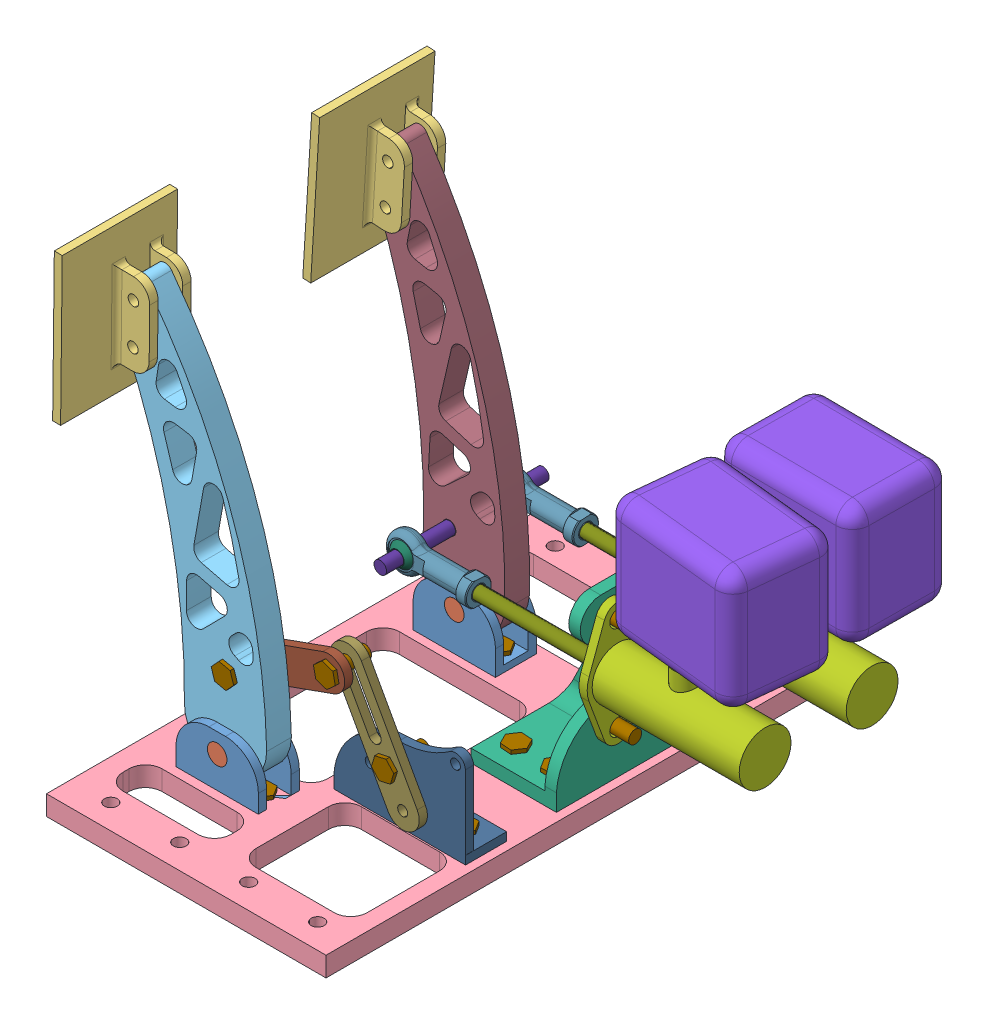
SolidWorks assembly Final Assembly, configuration Default. Lengths in mm.
Overall size (296.55 297.46 300.01).
42 component instances, 17 part files, 74 mates.
Components (placement in the parent):
- braket1-4: braket1 [Default] at (-141.1694 -572.6456 150.5631) size (50.04 35.05 24.89)
- screw-4: screw [Default] at (-131.3986 -621.8907 144.9751) size (24.68 21.38 30.48)
- throttle pedal-2: throttle pedal [Default] at (-246.1503 -359.0147 167.9481) x (0 0 -1) z (0.998164 -0.060575 0) size (70.1 89.92 24.82)
- pedal box base-2: pedal box base [Default] at (-213.3196 -624.1778 279.5672) x (-0.00023 0 1) z (0 1 0) size (299.97 169.93 11.99)
- braket1-5: braket1 [Default] at (-141.1997 -576.7096 294.5962) x (1 0 0.00023) z (-0.00023 0 1) size (50.04 35.05 24.89)
- throttle bar-3: throttle bar [Default] at (-198.6716 -410.0837 299.536) x (0.999937 -0.011241 0.00023) z (-0.00023 0 1) size (88.75 235.49 14.99)
- throttle pedal-3: throttle pedal [Default] at (-257.4721 -366.0384 311.9545) x (0.00023 0 -1) z (0.999937 -0.011241 0.00023) size (70.1 89.92 24.82)
- screw-5: screw [Default] at (-131.4275 -625.9547 289.0104) x (1 0 0.00023) z (-0.00023 0 1) size (24.68 21.38 30.48)
- brake holder 2-2: brake holder 2 [Default] at (-77.2892 -529.542 159.1215) x (-0.00023 0 1) z (-1 0 -0.00023) size (129.92 100.94 51.96)
- master cylinder-1: master cylinder [Default] at (-72.3192 -552.372 195.428) x (-0.00023 0 1) z (-1 0 -0.00023) size (37.59 74.93 94.34)
- master cylinder-2: master cylinder [Default] at (-72.3042 -552.372 130.404) x (-0.00023 0 1) z (-1 0 -0.00023) size (37.59 74.93 94.34)
- reservoir-1: reservoir [Default] at (-28.0647 -433.5 171.0985) x (-0.00841 0 0.999965) z (0 -1 0) size (59.69 84.07 93.98)
- reservoir-2: reservoir [Default] at (-31.9608 -433.5 236.2853) x (-0.103359 0 0.994644) z (0 -1 0) size (59.69 84.07 93.98)
- screw2-2: screw2 [Default] at (-195.652 -605.839 156.9169) x (1 0 0) z (0 -1 0) size (13.97 12.36 24.64)
- screw2-3: screw2 [Default] at (-165.68 -605.839 156.9169) x (1 0 0) z (0 -1 0) size (13.97 12.36 24.64)
- screw2-4: screw2 [Default] at (-195.6851 -609.903 300.9349) x (1 0 0) z (0 -1 0) size (13.97 12.36 24.64)
- screw2-5: screw2 [Default] at (-165.7131 -609.903 300.9418) x (1 0 0) z (0 -1 0) size (13.97 12.36 24.64)
- screw2-6: screw2 [Default] at (-86.566 -529.8891 119.0806) x (0.00023 0 -1) z (1 0 0.00023) size (13.97 12.36 24.64)
- screw2-7: screw2 [Default] at (-86.581 -517.7001 184.1072) x (0.000127 0.834841 -0.550491) z (1 0 0.00023) size (13.97 12.36 24.64)
- screw2-8: screw2 [Default] at (-86.5831 -568.29 193.1755) x (-0.000072 0.949913 0.312516) z (1 0 0.00023) size (13.97 12.36 24.64)
- screw2-9: screw2 [Default] at (-86.5715 -584.4532 142.7686) x (-0.000165 -0.696104 0.717941) z (1 0 0.00023) size (13.97 12.36 24.64)
- throttle link holder-1: throttle link holder [Default] at (-136.2849 -547.7292 283.2435) x (-1 0 -0.00023) z (0.00023 0 -1) size (80.01 56.04 24.97)
- screw2-10: screw2 [Default] at (-80.8684 -604.823 263.1153) x (1 0 0) z (0 -1 0) size (13.97 12.36 24.64)
- screw2-11: screw2 [Default] at (-105.7245 -602.029 106.8996) x (1 0 0) z (0 -1 0) size (13.97 12.36 24.64)
- screw2-12: screw2 [Default] at (-80.8325 -602.029 106.9053) x (1 0 0) z (0 -1 0) size (13.97 12.36 24.64)
- screw2-13: screw2 [Default] at (-139.2903 -604.823 256.6805) x (0.662504 0 -0.749058) z (0 -1 0) size (13.97 12.36 24.64)
- screw2-14: screw2 [Default] at (-80.8555 -602.029 206.8573) x (1 0 0) z (0 -1 0) size (13.97 12.36 24.64)
- screw2-15: screw2 [Default] at (-127.2522 -602.029 205.0994) x (-0.408462 0 -0.912775) z (0 -1 0) size (13.97 12.36 24.64)
- link2-1: link2 [Default] at (-162.0656 -546.6237 294.566) x (0.941416 0.337249 0.000216) z (-0.00023 0 1) size (70.1 20.07 4.98)
- link1-1: link1 [Default] at (-128.4449 -575.7285 283.2453) x (0.483636 -0.875269 0.000111) z (-0.00023 0 1) size (90.26 20.15 4.98)
- screw2-17: screw2 [Default] at (-203.9237 -556.3573 316.8068) x (-0.968749 0.248043 -0.000223) z (0.00023 0 -1) size (13.97 12.36 24.64)
- screw2-18: screw2 [Default] at (-118.1953 -592.8933 290.5121) x (-0.335719 -0.941962 -0.000077) z (0.00023 0 -1) size (13.97 12.36 24.64)
- screw2-21: screw2 [Default] at (-131.6018 -534.6293 301.8374) x (0.937139 -0.348957 0.000215) z (0.00023 0 -1) size (13.97 12.36 24.64)
- brake pedal bar2-1: brake pedal bar2 [Default] at (-189.598 -405.9081 155.5161) x (0.998164 -0.060575 0) z (0 0 1) size (88.75 235.49 14.99)
- rotula-1: rotula [Default] at (-199.8553 -552.0509 124.3889) x (-0.000012 0.998565 0.053558) z (-0.00023 -0.053558 0.998565) size (22.31 54.17 16)
- rotula2-1: rotula2 [Default] at (-199.8567 -552.3723 138.3813) x (-0.466077 0.884744 0) z (-0.884744 -0.466077 0) size (16 13.43 16)
- master cy plunge-4: master cy plunge [Default] at (-38.7407 -560.307 138.1282) x (0.000067 -0.956892 -0.290446) z (-1 0 -0.00023) size (25.4 25.4 118.11)
- master cy plunge-5: master cy plunge [Default] at (-38.7514 -550.0649 184.7345) x (0.000067 0.956892 -0.290446) z (-1 0 -0.00023) size (25.4 25.4 118.11)
- rotula-3: rotula [Default] at (-199.873 -552.0509 201.5085) x (-0.000012 -0.998565 0.053558) z (0.00023 -0.053558 -0.998565) size (22.31 54.17 16)
- rotula2-3: rotula2 [Default] at (-199.868 -552.3723 187.5161) x (-0.466077 0.884744 -0.000214) z (0.884744 0.466077 0.000407) size (16 13.43 16)
- rod-1: rod [Default] at (-188.1558 -556.2726 113.6061) size (7.62 7.62 41.91)
- rod-2: rod [Default] at (-188.1558 -556.2726 170.5021) size (7.62 7.62 41.91)
Mates (geometry in assembly coordinates):
- Concentric27: concentric anti-aligned: circle of braket1-4; circle of screw-4
- Coincident27: coincident aligned: circle of braket1-4; circle of screw-4
- Coincident28: coincident aligned: circle of braket1-4; circle of pedal box base-2
- Coincident29: coincident aligned: circle of braket1-4; circle of pedal box base-2
- Concentric29: concentric aligned: circle of pedal box base-2; circle of braket1-5
- Coincident32: coincident aligned: circle of pedal box base-2; circle of braket1-5
- Coincident33: coincident aligned: circle of pedal box base-2; circle of braket1-5
- Coincident35: coincident aligned: circle of braket1-5; circle of throttle bar-3
- Concentric30: concentric anti-aligned: circle of braket1-5; circle of throttle bar-3
- Concentric31: concentric anti-aligned: circle of throttle bar-3; circle of throttle pedal-3
- Concentric32: concentric anti-aligned: circle of throttle bar-3; circle of throttle pedal-3
- Coincident36: coincident anti-aligned: plane of throttle bar-3 through (-198.6716 -410.0837 299.536) normal (0.00023 0 -1); plane of throttle pedal-3 through (-232.6646 -367.1725 299.5282) normal (-0.00023 0 1)
- Concentric33: concentric anti-aligned: circle of braket1-5; circle of screw-5
- Coincident37: coincident aligned: circle of braket1-5; circle of screw-5
- Concentric40: concentric aligned: circle of pedal box base-2; circle of brake holder 2-2
- Concentric41: concentric aligned: circle of pedal box base-2; circle of brake holder 2-2
- Coincident48: coincident anti-aligned: plane of pedal box base-2 through (-213.3196 -612.189 279.5672) normal (0 1 0); plane of brake holder 2-2 through (-84.2752 -612.189 97.8892) normal (0 -1 0)
- Concentric49: concentric aligned: circle of brake holder 2-2; circle of master cylinder-2
- Concentric50: concentric aligned: circle of brake holder 2-2; circle of master cylinder-2
- Coincident52: coincident aligned: circle of brake holder 2-2; circle of master cylinder-2
- Concentric51: concentric aligned: circle of brake holder 2-2; circle of master cylinder-1
- Concentric52: concentric aligned: circle of brake holder 2-2; circle of master cylinder-1
- Coincident53: coincident aligned: circle of brake holder 2-2; circle of master cylinder-1
- Coincident55: coincident anti-aligned: circle of master cylinder-2; circle of reservoir-1
- Coincident56: coincident anti-aligned: circle of master cylinder-1; circle of reservoir-2
- Coincident59: coincident anti-aligned: circle of braket1-4; circle of screw2-2
- Coincident60: coincident anti-aligned: circle of braket1-4; circle of screw2-3
- Coincident61: coincident anti-aligned: circle of braket1-5; circle of screw2-4
- Coincident62: coincident anti-aligned: circle of pedal box base-2; circle of screw2-5
- Concentric62: concentric anti-aligned: circle of brake holder 2-2; circle of screw2-6
- Coincident64: coincident anti-aligned: plane of brake holder 2-2 through (-84.2892 -529.542 159.1199) normal (-1 0 -0.00023); circle of screw2-6
- Concentric63: concentric anti-aligned: circle of brake holder 2-2; circle of screw2-9
- Coincident65: coincident anti-aligned: plane of brake holder 2-2 through (-84.2892 -529.542 159.1199) normal (-1 0 -0.00023); circle of screw2-9
- Concentric64: concentric anti-aligned: circle of brake holder 2-2; circle of screw2-7
- Coincident66: coincident anti-aligned: plane of brake holder 2-2 through (-84.2892 -529.542 159.1199) normal (-1 0 -0.00023); circle of screw2-7
- Concentric65: concentric anti-aligned: circle of brake holder 2-2; circle of screw2-8
- Coincident67: coincident anti-aligned: plane of brake holder 2-2 through (-84.2892 -529.542 159.1199) normal (-1 0 -0.00023); circle of screw2-8
- Coincident68: coincident aligned: circle of pedal box base-2; circle of throttle link holder-1
- Concentric69: concentric anti-aligned: circle of pedal box base-2; circle of throttle link holder-1
- Concentric71: concentric anti-aligned: circle of brake holder 2-2; circle of screw2-12
- Coincident70: coincident anti-aligned: circle of brake holder 2-2; circle of screw2-12
- Concentric72: concentric anti-aligned: circle of brake holder 2-2; circle of screw2-11
- Coincident71: coincident anti-aligned: circle of brake holder 2-2; circle of screw2-11
- Concentric73: concentric anti-aligned: circle of brake holder 2-2; circle of screw2-15
- Coincident72: coincident anti-aligned: circle of brake holder 2-2; circle of screw2-15
- Concentric74: concentric anti-aligned: circle of brake holder 2-2; circle of screw2-14
- Coincident73: coincident anti-aligned: circle of brake holder 2-2; circle of screw2-14
- Concentric76: concentric aligned: circle of throttle link holder-1; circle of screw2-13
- Coincident75: coincident aligned: circle of throttle link holder-1; circle of screw2-13
- Concentric77: concentric anti-aligned: circle of throttle link holder-1; circle of screw2-10
- Coincident76: coincident anti-aligned: circle of throttle link holder-1; circle of screw2-10
- Concentric78: concentric aligned: cylinder of throttle bar-3 through (-191.4391 -553.2635 285.8216) axis (-0.00023 0 1) radius 3.937; circle of link2-1
- Coincident79: coincident anti-aligned: circle of throttle link holder-1; circle of link1-1
- Concentric80: concentric anti-aligned: cylinder of link2-1 through (-191.4411 -553.2635 294.5592) axis (-0.00023 0 1) radius 3.937; circle of screw2-17
- Coincident80: coincident anti-aligned: plane of throttle bar-3 through (-198.675 -410.0837 314.522) normal (-0.00023 0 1); circle of screw2-17
- Concentric82: concentric anti-aligned: circle of link1-1; circle of screw2-18
- Coincident82: coincident anti-aligned: plane of link1-1 through (-144.3331 -536.3882 288.2201) normal (-0.00023 0 1); circle of screw2-18
- Concentric98: concentric anti-aligned: circle of link2-1; circle of screw2-21
- Coincident96: coincident anti-aligned: plane of link2-1 through (-191.4422 -553.2635 299.5376) normal (-0.00023 0 1); circle of screw2-21
- Concentric99: concentric anti-aligned: circle of link1-1; circle of screw2-21
- Concentric100: concentric aligned: cylinder of screw-4 through (-191.8591 -589.075 175.4551) axis (0 0 -1) radius 5.969; cylinder of brake pedal bar2-1 through (-191.8591 -589.075 170.5021) axis (0 0 -1) radius 5.969
- Coincident97: coincident anti-aligned: plane of braket1-4 through (-216.8781 -664.4229 155.5161) normal (0 0 1); plane of brake pedal bar2-1 through (-189.598 -405.9081 155.5161) normal (0 0 -1)
- Concentric101: concentric anti-aligned: cylinder of throttle pedal-2 through (-232.0813 -373.3215 204.4619) axis (0 0 -1) radius 3.1963; cylinder of brake pedal bar2-1 through (-232.0813 -373.3215 141.8001) axis (0 0 1) radius 3.048
- Concentric102: concentric anti-aligned: cylinder of throttle pedal-2 through (-233.5892 -398.1678 204.4619) axis (0 0 -1) radius 3.1963; cylinder of brake pedal bar2-1 through (-233.5892 -398.1678 141.8001) axis (0 0 1) radius 3.048
- Coincident99: coincident anti-aligned: plane of throttle pedal-2 through (-221.4319 -361.3716 170.5021) normal (0 0 -1); plane of brake pedal bar2-1 through (-189.598 -405.9081 170.5021) normal (0 0 1)
- Concentric115: concentric anti-aligned: circle of rotula-1; circle of master cy plunge-4
- Concentric120: concentric: sphere of rotula-1; sphere of rotula2-1
- Concentric122: concentric aligned: cylinder of master cylinder-2 through (-77.2826 -552.372 130.4029) axis (1 0 0.00023) radius 12.7; cylinder of master cy plunge-4 through (-156.8489 -552.372 130.3846) axis (1 0 0.00023) radius 3.937
- Coincident104: coincident anti-aligned: plane of rotula-1 through (-156.8489 -552.372 130.3846) normal (1 0 0.00023); plane of master cy plunge-4 through (-156.8489 -552.372 130.3846) normal (-1 0 -0.00023)
- Concentric126: concentric aligned: cylinder of brake pedal bar2-1 through (-199.8567 -552.3723 181.4241) axis (0 0 -1) radius 4.064; cylinder of rotula2-1 through (-199.8567 -552.3723 138.3813) axis (0 0 -1) radius 3.937
- Concentric127: concentric anti-aligned: circle of brake pedal bar2-1; circle of rod-1
- Coincident105: coincident anti-aligned: plane of brake pedal bar2-1 through (-189.598 -405.9081 155.5161) normal (0 0 -1); circle of rod-1
- Concentric129: concentric anti-aligned: circle of brake pedal bar2-1; cylinder of rod-2 through (-199.8567 -552.3723 212.4121) axis (0 0 -1) radius 3.81
- Coincident107: coincident aligned: plane of brake pedal bar2-1 through (-189.598 -405.9081 170.5021) normal (0 0 1); circle of rod-2
